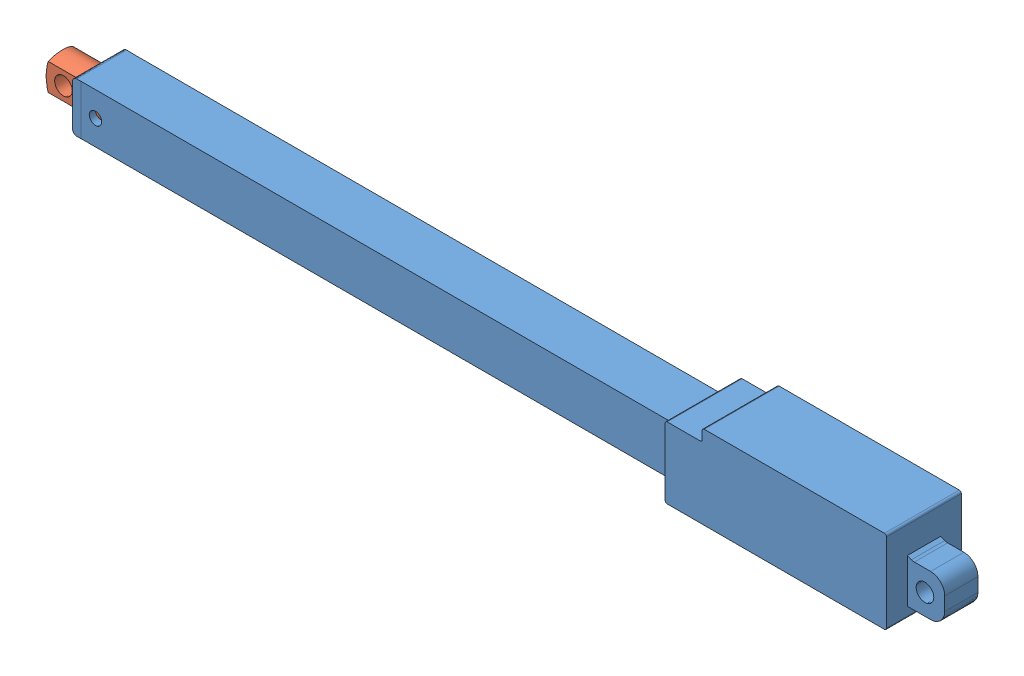
SolidWorks assembly actuator assembly, configuration Default. Lengths in mm.
Overall size (217 20 18).
2 component instances, 2 part files, 3 mates.
Components (placement in the parent):
- actuator body-2: actuator body [Default] at (-281.2868 100.6339 -12.1544) size (207.68 20 18)
- actuator arm-2: actuator arm [Default] at (-282.2868 102.1564 -12.1044) size (147.32 8.9 8.9)
Mates (geometry in assembly coordinates):
- Concentric2: concentric anti-aligned: cylinder of actuator body-2 through (-143.2868 106.6064 -12.1544) axis (-1 0 0) radius 4.45; cylinder of actuator arm-2 through (-343.2868 106.6064 -12.1544) axis (1 0 0) radius 4.45
- Parallel1: parallel aligned: plane of actuator body-2 through (-281.2868 100.6339 -6.1794) normal (0 0 1); plane of actuator arm-2 through (-282.2868 102.1564 -9.1044) normal (0 0 1)
- LimitDistance1: limit distance = 0 mm anti-aligned: plane of actuator arm-2 through (-143.2868 102.1564 -7.6044) normal (1 0 0); plane of actuator body-2 through (-143.2868 106.6064 -12.1544) normal (-1 0 0)
